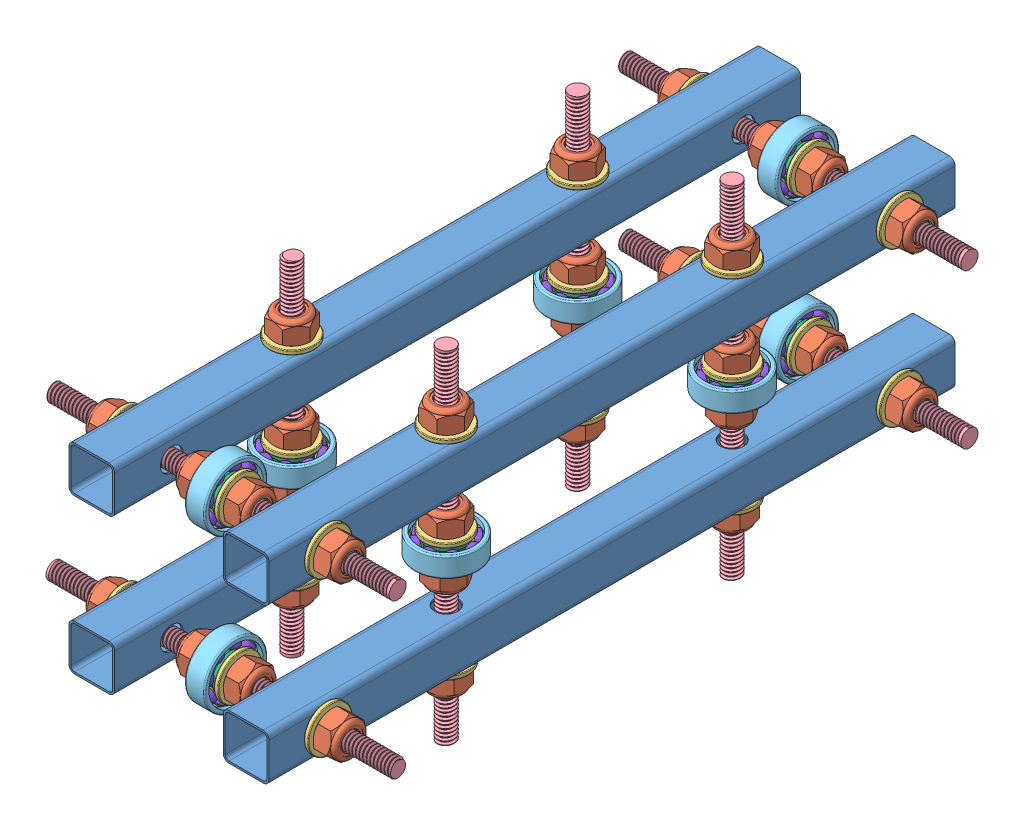
SolidWorks assembly CNC_SubAssembly_RotorArm, configuration Default. Lengths in mm.
Overall size (122.22 122.22 240).
180 component instances, 8 part files, 138 mates.
Components (placement in the parent):
- Square_Tubing_16mm-1: Square_Tubing_16mm [Default] at (-80.5305 46.7457 -574.3307) size (16 16 240)
- Square_Tubing_16mm-2: Square_Tubing_16mm [Default] at (-80.5305 -7.2543 -574.3307) size (16 16 240)
- Square_Tubing_16mm-3: Square_Tubing_16mm [Default] at (-134.5305 -7.2543 -574.3307) size (16 16 240)
- Square_Tubing_16mm-4: Square_Tubing_16mm [Default] at (-134.5305 46.7457 -574.3307) size (16 16 240)
- M8_self_lock_Nut-1: M8_self_lock_Nut [Valor predeterminado] at (-134.5305 -22.7543 -624.3307) x (0.853939 0 -0.520374) z (0 1 0) size (15.1 12 8.06)
- M8_Washer-1: M8_Washer [Default] at (-144.0305 46.7457 -674.3307) x (0 -0.853939 -0.520374) z (1 0 0) size (15.5 15.5 1.5)
- M8_self_lock_Nut-2: M8_self_lock_Nut [Valor predeterminado] at (-80.5305 -22.7543 -524.3307) x (0.853939 0 -0.520374) z (0 1 0) size (15.1 12 8.06)
- M8_self_lock_Nut-3: M8_self_lock_Nut [Valor predeterminado] at (-134.5305 62.2457 -624.3307) x (-0.430276 0 -0.902697) z (0 -1 0) size (15.1 12 8.06)
- M8_self_lock_Nut-4: M8_self_lock_Nut [Valor predeterminado] at (-80.5305 62.2457 -624.3307) x (-0.430276 0 -0.902697) z (0 -1 0) size (15.1 12 8.06)
- M8_self_lock_Nut-5: M8_self_lock_Nut [Valor predeterminado] at (-80.5305 -22.7543 -624.3307) x (0.853939 0 -0.520374) z (0 1 0) size (15.1 12 8.06)
- M8_self_lock_Nut-6: M8_self_lock_Nut [Valor predeterminado] at (-80.5305 62.2457 -524.3307) x (-0.430276 0 -0.902697) z (0 -1 0) size (15.1 12 8.06)
- M8_self_lock_Nut-7: M8_self_lock_Nut [Valor predeterminado] at (-134.5305 -22.7543 -524.3307) x (0.853939 0 -0.520374) z (0 1 0) size (15.1 12 8.06)
- M8_self_lock_Nut-8: M8_self_lock_Nut [Valor predeterminado] at (-134.5305 62.2457 -524.3307) x (-0.430276 0 -0.902697) z (0 -1 0) size (15.1 12 8.06)
- M8_Washer-2: M8_Washer [Default] at (-134.5305 56.2457 -624.3307) x (-0.853939 0 -0.520374) z (0 -1 0) size (15.5 15.5 1.5)
- M8_Washer-3: M8_Washer [Default] at (-80.5305 56.2457 -624.3307) x (-0.853939 0 -0.520374) z (0 -1 0) size (15.5 15.5 1.5)
- M8_Washer-4: M8_Washer [Default] at (-144.0305 -7.2543 -674.3307) x (0 -0.853939 -0.520374) z (1 0 0) size (15.5 15.5 1.5)
- M8_Washer-5: M8_Washer [Default] at (-72.5305 46.7457 -474.3307) x (0 -0.853939 -0.520374) z (1 0 0) size (15.5 15.5 1.5)
- M8_Washer-6: M8_Washer [Default] at (-80.5305 56.2457 -524.3307) x (-0.853939 0 -0.520374) z (0 -1 0) size (15.5 15.5 1.5)
- M8_Washer-7: M8_Washer [Default] at (-72.5305 46.7457 -674.3307) x (0 -0.853939 -0.520374) z (1 0 0) size (15.5 15.5 1.5)
- M8_Washer-8: M8_Washer [Default] at (-72.5305 -7.2543 -474.3307) x (0 -0.853939 -0.520374) z (1 0 0) size (15.5 15.5 1.5)
- M8_Washer-9: M8_Washer [Default] at (-134.5305 56.2457 -524.3307) x (-0.853939 0 -0.520374) z (0 -1 0) size (15.5 15.5 1.5)
- M8_Washer-10: M8_Washer [Default] at (-144.0305 -7.2543 -474.3307) x (0 -0.853939 -0.520374) z (1 0 0) size (15.5 15.5 1.5)
- M8_Washer-11: M8_Washer [Default] at (-144.0305 46.7457 -474.3307) x (0 -0.853939 -0.520374) z (1 0 0) size (15.5 15.5 1.5)
- M8_Washer-12: M8_Washer [Default] at (-72.5305 -7.2543 -674.3307) x (0 -0.853939 -0.520374) z (1 0 0) size (15.5 15.5 1.5)
- M8_Washer-13: M8_Washer [Default] at (-80.5305 -15.2543 -524.3307) x (-0.853939 0 -0.520374) z (0 -1 0) size (15.5 15.5 1.5)
- M8_Washer-14: M8_Washer [Default] at (-134.5305 -15.2543 -624.3307) x (-0.853939 0 -0.520374) z (0 -1 0) size (15.5 15.5 1.5)
- M8_Washer-15: M8_Washer [Default] at (-134.5305 -15.2543 -524.3307) x (-0.853939 0 -0.520374) z (0 -1 0) size (15.5 15.5 1.5)
- M8_Washer-16: M8_Washer [Default] at (-80.5305 -15.2543 -624.3307) x (-0.853939 0 -0.520374) z (0 -1 0) size (15.5 15.5 1.5)
- M8_self_lock_Nut-13: M8_self_lock_Nut [Valor predeterminado] at (-65.0305 -7.2543 -674.3307) x (0 0.669995 0.742366) z (-1 0 0) size (15.1 12 8.06)
- M8_self_lock_Nut-14: M8_self_lock_Nut [Valor predeterminado] at (-65.0305 46.7457 -474.3307) x (0 0.669995 0.742366) z (-1 0 0) size (15.1 12 8.06)
- M8_self_lock_Nut-15: M8_self_lock_Nut [Valor predeterminado] at (-65.0305 -7.2543 -474.3307) x (0 0.669995 0.742366) z (-1 0 0) size (15.1 12 8.06)
- M8_self_lock_Nut-16: M8_self_lock_Nut [Valor predeterminado] at (-65.0305 46.7457 -674.3307) x (0 0.669995 0.742366) z (-1 0 0) size (15.1 12 8.06)
- M8_self_lock_Nut-17: M8_self_lock_Nut [Valor predeterminado] at (-150.0305 46.7457 -674.3307) x (0 -0.430276 -0.902697) z (1 0 0) size (15.1 12 8.06)
- M8_self_lock_Nut-18: M8_self_lock_Nut [Valor predeterminado] at (-150.0305 -7.2543 -474.3307) x (0 -0.430276 -0.902697) z (1 0 0) size (15.1 12 8.06)
- M8_self_lock_Nut-19: M8_self_lock_Nut [Valor predeterminado] at (-150.0305 46.7457 -474.3307) x (0 -0.430276 -0.902697) z (1 0 0) size (15.1 12 8.06)
- M8_self_lock_Nut-20: M8_self_lock_Nut [Valor predeterminado] at (-150.0305 -7.2543 -674.3307) x (0 -0.430276 -0.902697) z (1 0 0) size (15.1 12 8.06)
- M8_Threaded_Rod-1: M8_Threaded_Rod [Default] at (-134.5305 -40.2543 -624.3307) size (6.18 121.11 6.93)
- M8_Threaded_Rod-2: M8_Threaded_Rod [Default] at (-167.5305 46.7457 -474.3307) x (0 -1 0) z (0 0 1) size (6.18 121.11 6.93)
- M8_Threaded_Rod-3: M8_Threaded_Rod [Default] at (-80.5305 -40.2543 -624.3307) size (6.18 121.11 6.93)
- M8_Threaded_Rod-4: M8_Threaded_Rod [Default] at (-167.5305 46.7457 -674.3307) x (0 -1 0) z (0 0 1) size (6.18 121.11 6.93)
- M8_Threaded_Rod-5: M8_Threaded_Rod [Default] at (-167.5305 -7.2543 -674.3307) x (0 -1 0) z (0 0 1) size (6.18 121.11 6.93)
- M8_Threaded_Rod-6: M8_Threaded_Rod [Default] at (-134.5305 79.7457 -524.3307) x (-1 0 0) z (0 0 1) size (6.18 121.11 6.93)
- BB_Assembly-2: BB_Assembly [Default] at (-107.5305 46.7457 -674.3307) size (7 22 22)
  - BB_OuterRing-1: BB_OuterRing [Default] at origin size (7 22 22)
  - BB_InnerRing-1: BB_InnerRing [Default] x (1 0 0) z (0 0.97954 -0.20125) size (7 13 13)
  - BB_Ball-1: BB_Ball [Default] at (0 1.61 7.8363) x (-1 0 0) z (0 -0.97954 0.20125) size (4.5 4.5 4.5)
  - BB_Cage-1: BB_Cage [Default] x (0 -0.20125 -0.97954) z (1 0 0) size (18 18 2.77)
  - BB_Ball-2: BB_Ball [Default] at (0 6.6796 4.4027) x (-1 0 0) z (0 -0.550334 0.834945) size (4.5 4.5 4.5)
  - BB_Ball-3: BB_Ball [Default] at (0 7.8363 -1.61) x (-1 0 0) z (0 0.20125 0.97954) size (4.5 4.5 4.5)
  - BB_Ball-4: BB_Ball [Default] at (0 4.4027 -6.6796) x (-1 0 0) z (0 0.834945 0.550334) size (4.5 4.5 4.5)
  - BB_Ball-5: BB_Ball [Default] at (0 -1.61 -7.8363) x (-1 0 0) z (0 0.97954 -0.20125) size (4.5 4.5 4.5)
  - BB_Ball-6: BB_Ball [Default] at (0 -6.6796 -4.4027) x (-1 0 0) z (0 0.550334 -0.834945) size (4.5 4.5 4.5)
  - BB_Ball-7: BB_Ball [Default] at (0 -7.8363 1.61) x (-1 0 0) z (0 -0.20125 -0.97954) size (4.5 4.5 4.5)
  - BB_Ball-8: BB_Ball [Default] at (0 -4.4027 6.6796) x (-1 0 0) z (0 -0.834945 -0.550334) size (4.5 4.5 4.5)
  - BB_Cage-2: BB_Cage [Default] x (0 0.20125 0.97954) z (-1 0 0) size (18 18 2.77)
- M8_Washer-18: M8_Washer [Default] at (-104.0305 46.7457 -674.3307) x (0 -0.853939 -0.520374) z (1 0 0) size (15.5 15.5 1.5)
- M8_Washer-19: M8_Washer [Default] at (-112.5305 46.7457 -674.3307) x (0 -0.853939 -0.520374) z (1 0 0) size (15.5 15.5 1.5)
- M8_self_lock_Nut-21: M8_self_lock_Nut [Valor predeterminado] at (-118.5305 46.7457 -674.3307) x (0 -0.430276 -0.902697) z (1 0 0) size (15.1 12 8.06)
- M8_self_lock_Nut-22: M8_self_lock_Nut [Valor predeterminado] at (-96.5305 46.7457 -674.3307) x (0 -0.463134 0.886288) z (-1 0 0) size (15.1 12 8.06)
- M8_self_lock_Nut-23: M8_self_lock_Nut [Valor predeterminado] at (-118.5305 46.7457 -474.3307) x (0 -0.430276 -0.902697) z (1 0 0) size (15.1 12 8.06)
- M8_Washer-20: M8_Washer [Default] at (-104.0305 46.7457 -474.3307) x (0 -0.853939 -0.520374) z (1 0 0) size (15.5 15.5 1.5)
- M8_Washer-21: M8_Washer [Default] at (-112.5305 46.7457 -474.3307) x (0 -0.853939 -0.520374) z (1 0 0) size (15.5 15.5 1.5)
- BB_Assembly-3: BB_Assembly [Default] at (-107.5305 46.7457 -474.3307) size (7 22 22)
  - BB_OuterRing-1: BB_OuterRing [Default] at origin size (7 22 22)
  - BB_InnerRing-1: BB_InnerRing [Default] x (1 0 0) z (0 0.97954 -0.20125) size (7 13 13)
  - BB_Ball-1: BB_Ball [Default] at (0 1.61 7.8363) x (-1 0 0) z (0 -0.97954 0.20125) size (4.5 4.5 4.5)
  - BB_Cage-1: BB_Cage [Default] x (0 -0.20125 -0.97954) z (1 0 0) size (18 18 2.77)
  - BB_Ball-2: BB_Ball [Default] at (0 6.6796 4.4027) x (-1 0 0) z (0 -0.550334 0.834945) size (4.5 4.5 4.5)
  - BB_Ball-3: BB_Ball [Default] at (0 7.8363 -1.61) x (-1 0 0) z (0 0.20125 0.97954) size (4.5 4.5 4.5)
  - BB_Ball-4: BB_Ball [Default] at (0 4.4027 -6.6796) x (-1 0 0) z (0 0.834945 0.550334) size (4.5 4.5 4.5)
  - BB_Ball-5: BB_Ball [Default] at (0 -1.61 -7.8363) x (-1 0 0) z (0 0.97954 -0.20125) size (4.5 4.5 4.5)
  - BB_Ball-6: BB_Ball [Default] at (0 -6.6796 -4.4027) x (-1 0 0) z (0 0.550334 -0.834945) size (4.5 4.5 4.5)
  - BB_Ball-7: BB_Ball [Default] at (0 -7.8363 1.61) x (-1 0 0) z (0 -0.20125 -0.97954) size (4.5 4.5 4.5)
  - BB_Ball-8: BB_Ball [Default] at (0 -4.4027 6.6796) x (-1 0 0) z (0 -0.834945 -0.550334) size (4.5 4.5 4.5)
  - BB_Cage-2: BB_Cage [Default] x (0 0.20125 0.97954) z (-1 0 0) size (18 18 2.77)
- M8_self_lock_Nut-24: M8_self_lock_Nut [Valor predeterminado] at (-96.5305 46.7457 -474.3307) x (0 -0.463134 0.886288) z (-1 0 0) size (15.1 12 8.06)
- M8_self_lock_Nut-25: M8_self_lock_Nut [Valor predeterminado] at (-134.5305 30.7457 -624.3307) x (-0.430276 0 -0.902697) z (0 -1 0) size (15.1 12 8.06)
- M8_Washer-22: M8_Washer [Default] at (-134.5305 16.2457 -624.3307) x (-0.853939 0 -0.520374) z (0 -1 0) size (15.5 15.5 1.5)
- M8_Washer-23: M8_Washer [Default] at (-134.5305 24.7457 -624.3307) x (-0.853939 0 -0.520374) z (0 -1 0) size (15.5 15.5 1.5)
- BB_Assembly-4: BB_Assembly [Default] at (-134.5305 19.7457 -624.3307) x (0 -1 0) z (0 0 1) size (7 22 22)
  - BB_OuterRing-1: BB_OuterRing [Default] at origin size (7 22 22)
  - BB_InnerRing-1: BB_InnerRing [Default] x (1 0 0) z (0 0.97954 -0.20125) size (7 13 13)
  - BB_Ball-1: BB_Ball [Default] at (0 1.61 7.8363) x (-1 0 0) z (0 -0.97954 0.20125) size (4.5 4.5 4.5)
  - BB_Cage-1: BB_Cage [Default] x (0 -0.20125 -0.97954) z (1 0 0) size (18 18 2.77)
  - BB_Ball-2: BB_Ball [Default] at (0 6.6796 4.4027) x (-1 0 0) z (0 -0.550334 0.834945) size (4.5 4.5 4.5)
  - BB_Ball-3: BB_Ball [Default] at (0 7.8363 -1.61) x (-1 0 0) z (0 0.20125 0.97954) size (4.5 4.5 4.5)
  - BB_Ball-4: BB_Ball [Default] at (0 4.4027 -6.6796) x (-1 0 0) z (0 0.834945 0.550334) size (4.5 4.5 4.5)
  - BB_Ball-5: BB_Ball [Default] at (0 -1.61 -7.8363) x (-1 0 0) z (0 0.97954 -0.20125) size (4.5 4.5 4.5)
  - BB_Ball-6: BB_Ball [Default] at (0 -6.6796 -4.4027) x (-1 0 0) z (0 0.550334 -0.834945) size (4.5 4.5 4.5)
  - BB_Ball-7: BB_Ball [Default] at (0 -7.8363 1.61) x (-1 0 0) z (0 -0.20125 -0.97954) size (4.5 4.5 4.5)
  - BB_Ball-8: BB_Ball [Default] at (0 -4.4027 6.6796) x (-1 0 0) z (0 -0.834945 -0.550334) size (4.5 4.5 4.5)
  - BB_Cage-2: BB_Cage [Default] x (0 0.20125 0.97954) z (-1 0 0) size (18 18 2.77)
- M8_self_lock_Nut-26: M8_self_lock_Nut [Valor predeterminado] at (-134.5305 8.7457 -624.3307) x (-0.463134 0 0.886288) z (0 1 0) size (15.1 12 8.06)
- M8_self_lock_Nut-29: M8_self_lock_Nut [Valor predeterminado] at (-96.5305 -7.2543 -674.3307) x (0 -0.463134 0.886288) z (-1 0 0) size (15.1 12 8.06)
- BB_Assembly-6: BB_Assembly [Default] at (-107.5305 -7.2543 -674.3307) size (7 22 22)
  - BB_OuterRing-1: BB_OuterRing [Default] at origin size (7 22 22)
  - BB_InnerRing-1: BB_InnerRing [Default] x (1 0 0) z (0 0.97954 -0.20125) size (7 13 13)
  - BB_Ball-1: BB_Ball [Default] at (0 1.61 7.8363) x (-1 0 0) z (0 -0.97954 0.20125) size (4.5 4.5 4.5)
  - BB_Cage-1: BB_Cage [Default] x (0 -0.20125 -0.97954) z (1 0 0) size (18 18 2.77)
  - BB_Ball-2: BB_Ball [Default] at (0 6.6796 4.4027) x (-1 0 0) z (0 -0.550334 0.834945) size (4.5 4.5 4.5)
  - BB_Ball-3: BB_Ball [Default] at (0 7.8363 -1.61) x (-1 0 0) z (0 0.20125 0.97954) size (4.5 4.5 4.5)
  - BB_Ball-4: BB_Ball [Default] at (0 4.4027 -6.6796) x (-1 0 0) z (0 0.834945 0.550334) size (4.5 4.5 4.5)
  - BB_Ball-5: BB_Ball [Default] at (0 -1.61 -7.8363) x (-1 0 0) z (0 0.97954 -0.20125) size (4.5 4.5 4.5)
  - BB_Ball-6: BB_Ball [Default] at (0 -6.6796 -4.4027) x (-1 0 0) z (0 0.550334 -0.834945) size (4.5 4.5 4.5)
  - BB_Ball-7: BB_Ball [Default] at (0 -7.8363 1.61) x (-1 0 0) z (0 -0.20125 -0.97954) size (4.5 4.5 4.5)
  - BB_Ball-8: BB_Ball [Default] at (0 -4.4027 6.6796) x (-1 0 0) z (0 -0.834945 -0.550334) size (4.5 4.5 4.5)
  - BB_Cage-2: BB_Cage [Default] x (0 0.20125 0.97954) z (-1 0 0) size (18 18 2.77)
- M8_Washer-26: M8_Washer [Default] at (-104.0305 -7.2543 -674.3307) x (0 -0.853939 -0.520374) z (1 0 0) size (15.5 15.5 1.5)
- M8_self_lock_Nut-30: M8_self_lock_Nut [Valor predeterminado] at (-118.5305 -7.2543 -674.3307) x (0 -0.430276 -0.902697) z (1 0 0) size (15.1 12 8.06)
- M8_Washer-27: M8_Washer [Default] at (-112.5305 -7.2543 -674.3307) x (0 -0.853939 -0.520374) z (1 0 0) size (15.5 15.5 1.5)
- M8_self_lock_Nut-31: M8_self_lock_Nut [Valor predeterminado] at (-80.5305 8.7457 -524.3307) x (-0.463134 0 0.886288) z (0 1 0) size (15.1 12 8.06)
- BB_Assembly-7: BB_Assembly [Default] at (-80.5305 19.7457 -524.3307) x (0 -1 0) z (0 0 1) size (7 22 22)
  - BB_OuterRing-1: BB_OuterRing [Default] at origin size (7 22 22)
  - BB_InnerRing-1: BB_InnerRing [Default] x (1 0 0) z (0 0.97954 -0.20125) size (7 13 13)
  - BB_Ball-1: BB_Ball [Default] at (0 1.61 7.8363) x (-1 0 0) z (0 -0.97954 0.20125) size (4.5 4.5 4.5)
  - BB_Cage-1: BB_Cage [Default] x (0 -0.20125 -0.97954) z (1 0 0) size (18 18 2.77)
  - BB_Ball-2: BB_Ball [Default] at (0 6.6796 4.4027) x (-1 0 0) z (0 -0.550334 0.834945) size (4.5 4.5 4.5)
  - BB_Ball-3: BB_Ball [Default] at (0 7.8363 -1.61) x (-1 0 0) z (0 0.20125 0.97954) size (4.5 4.5 4.5)
  - BB_Ball-4: BB_Ball [Default] at (0 4.4027 -6.6796) x (-1 0 0) z (0 0.834945 0.550334) size (4.5 4.5 4.5)
  - BB_Ball-5: BB_Ball [Default] at (0 -1.61 -7.8363) x (-1 0 0) z (0 0.97954 -0.20125) size (4.5 4.5 4.5)
  - BB_Ball-6: BB_Ball [Default] at (0 -6.6796 -4.4027) x (-1 0 0) z (0 0.550334 -0.834945) size (4.5 4.5 4.5)
  - BB_Ball-7: BB_Ball [Default] at (0 -7.8363 1.61) x (-1 0 0) z (0 -0.20125 -0.97954) size (4.5 4.5 4.5)
  - BB_Ball-8: BB_Ball [Default] at (0 -4.4027 6.6796) x (-1 0 0) z (0 -0.834945 -0.550334) size (4.5 4.5 4.5)
  - BB_Cage-2: BB_Cage [Default] x (0 0.20125 0.97954) z (-1 0 0) size (18 18 2.77)
- M8_Washer-28: M8_Washer [Default] at (-80.5305 16.2457 -524.3307) x (-0.853939 0 -0.520374) z (0 -1 0) size (15.5 15.5 1.5)
- M8_self_lock_Nut-32: M8_self_lock_Nut [Valor predeterminado] at (-80.5305 30.7457 -524.3307) x (-0.430276 0 -0.902697) z (0 -1 0) size (15.1 12 8.06)
- M8_Washer-29: M8_Washer [Default] at (-80.5305 24.7457 -524.3307) x (-0.853939 0 -0.520374) z (0 -1 0) size (15.5 15.5 1.5)
- M8_self_lock_Nut-33: M8_self_lock_Nut [Valor predeterminado] at (-118.5305 -7.2543 -474.3307) x (0 -0.430276 -0.902697) z (1 0 0) size (15.1 12 8.06)
- M8_Washer-30: M8_Washer [Default] at (-104.0305 -7.2543 -474.3307) x (0 -0.853939 -0.520374) z (1 0 0) size (15.5 15.5 1.5)
- M8_Washer-31: M8_Washer [Default] at (-112.5305 -7.2543 -474.3307) x (0 -0.853939 -0.520374) z (1 0 0) size (15.5 15.5 1.5)
- BB_Assembly-8: BB_Assembly [Default] at (-107.5305 -7.2543 -474.3307) size (7 22 22)
  - BB_OuterRing-1: BB_OuterRing [Default] at origin size (7 22 22)
  - BB_InnerRing-1: BB_InnerRing [Default] x (1 0 0) z (0 0.97954 -0.20125) size (7 13 13)
  - BB_Ball-1: BB_Ball [Default] at (0 1.61 7.8363) x (-1 0 0) z (0 -0.97954 0.20125) size (4.5 4.5 4.5)
  - BB_Cage-1: BB_Cage [Default] x (0 -0.20125 -0.97954) z (1 0 0) size (18 18 2.77)
  - BB_Ball-2: BB_Ball [Default] at (0 6.6796 4.4027) x (-1 0 0) z (0 -0.550334 0.834945) size (4.5 4.5 4.5)
  - BB_Ball-3: BB_Ball [Default] at (0 7.8363 -1.61) x (-1 0 0) z (0 0.20125 0.97954) size (4.5 4.5 4.5)
  - BB_Ball-4: BB_Ball [Default] at (0 4.4027 -6.6796) x (-1 0 0) z (0 0.834945 0.550334) size (4.5 4.5 4.5)
  - BB_Ball-5: BB_Ball [Default] at (0 -1.61 -7.8363) x (-1 0 0) z (0 0.97954 -0.20125) size (4.5 4.5 4.5)
  - BB_Ball-6: BB_Ball [Default] at (0 -6.6796 -4.4027) x (-1 0 0) z (0 0.550334 -0.834945) size (4.5 4.5 4.5)
  - BB_Ball-7: BB_Ball [Default] at (0 -7.8363 1.61) x (-1 0 0) z (0 -0.20125 -0.97954) size (4.5 4.5 4.5)
  - BB_Ball-8: BB_Ball [Default] at (0 -4.4027 6.6796) x (-1 0 0) z (0 -0.834945 -0.550334) size (4.5 4.5 4.5)
  - BB_Cage-2: BB_Cage [Default] x (0 0.20125 0.97954) z (-1 0 0) size (18 18 2.77)
- M8_self_lock_Nut-34: M8_self_lock_Nut [Valor predeterminado] at (-96.5305 -7.2543 -474.3307) x (0 -0.463134 0.886288) z (-1 0 0) size (15.1 12 8.06)
- M8_self_lock_Nut-35: M8_self_lock_Nut [Valor predeterminado] at (-134.5305 8.7457 -524.3307) x (0.430276 0 -0.902697) z (0 1 0) size (15.1 12 8.06)
- M8_Washer-32: M8_Washer [Default] at (-134.5305 23.2457 -524.3307) x (0.853939 0 -0.520374) z (0 1 0) size (15.5 15.5 1.5)
- M8_Washer-33: M8_Washer [Default] at (-134.5305 14.7457 -524.3307) x (0.853939 0 -0.520374) z (0 1 0) size (15.5 15.5 1.5)
- BB_Assembly-9: BB_Assembly [Default] at (-134.5305 19.7457 -524.3307) x (0 1 0) z (0 0 1) size (7 22 22)
  - BB_OuterRing-1: BB_OuterRing [Default] at origin size (7 22 22)
  - BB_InnerRing-1: BB_InnerRing [Default] x (1 0 0) z (0 0.97954 -0.20125) size (7 13 13)
  - BB_Ball-1: BB_Ball [Default] at (0 1.61 7.8363) x (-1 0 0) z (0 -0.97954 0.20125) size (4.5 4.5 4.5)
  - BB_Cage-1: BB_Cage [Default] x (0 -0.20125 -0.97954) z (1 0 0) size (18 18 2.77)
  - BB_Ball-2: BB_Ball [Default] at (0 6.6796 4.4027) x (-1 0 0) z (0 -0.550334 0.834945) size (4.5 4.5 4.5)
  - BB_Ball-3: BB_Ball [Default] at (0 7.8363 -1.61) x (-1 0 0) z (0 0.20125 0.97954) size (4.5 4.5 4.5)
  - BB_Ball-4: BB_Ball [Default] at (0 4.4027 -6.6796) x (-1 0 0) z (0 0.834945 0.550334) size (4.5 4.5 4.5)
  - BB_Ball-5: BB_Ball [Default] at (0 -1.61 -7.8363) x (-1 0 0) z (0 0.97954 -0.20125) size (4.5 4.5 4.5)
  - BB_Ball-6: BB_Ball [Default] at (0 -6.6796 -4.4027) x (-1 0 0) z (0 0.550334 -0.834945) size (4.5 4.5 4.5)
  - BB_Ball-7: BB_Ball [Default] at (0 -7.8363 1.61) x (-1 0 0) z (0 -0.20125 -0.97954) size (4.5 4.5 4.5)
  - BB_Ball-8: BB_Ball [Default] at (0 -4.4027 6.6796) x (-1 0 0) z (0 -0.834945 -0.550334) size (4.5 4.5 4.5)
  - BB_Cage-2: BB_Cage [Default] x (0 0.20125 0.97954) z (-1 0 0) size (18 18 2.77)
- M8_self_lock_Nut-36: M8_self_lock_Nut [Valor predeterminado] at (-134.5305 30.7457 -524.3307) x (0.463134 0 0.886288) z (0 -1 0) size (15.1 12 8.06)
- M8_self_lock_Nut-37: M8_self_lock_Nut [Valor predeterminado] at (-80.5305 30.7457 -624.3307) x (-0.430276 0 -0.902697) z (0 -1 0) size (15.1 12 8.06)
- M8_Washer-34: M8_Washer [Default] at (-80.5305 16.2457 -624.3307) x (-0.853939 0 -0.520374) z (0 -1 0) size (15.5 15.5 1.5)
- M8_Washer-35: M8_Washer [Default] at (-80.5305 24.7457 -624.3307) x (-0.853939 0 -0.520374) z (0 -1 0) size (15.5 15.5 1.5)
- BB_Assembly-10: BB_Assembly [Default] at (-80.5305 19.7457 -624.3307) x (0 -1 0) z (0 0 1) size (7 22 22)
  - BB_OuterRing-1: BB_OuterRing [Default] at origin size (7 22 22)
  - BB_InnerRing-1: BB_InnerRing [Default] x (1 0 0) z (0 0.97954 -0.20125) size (7 13 13)
  - BB_Ball-1: BB_Ball [Default] at (0 1.61 7.8363) x (-1 0 0) z (0 -0.97954 0.20125) size (4.5 4.5 4.5)
  - BB_Cage-1: BB_Cage [Default] x (0 -0.20125 -0.97954) z (1 0 0) size (18 18 2.77)
  - BB_Ball-2: BB_Ball [Default] at (0 6.6796 4.4027) x (-1 0 0) z (0 -0.550334 0.834945) size (4.5 4.5 4.5)
  - BB_Ball-3: BB_Ball [Default] at (0 7.8363 -1.61) x (-1 0 0) z (0 0.20125 0.97954) size (4.5 4.5 4.5)
  - BB_Ball-4: BB_Ball [Default] at (0 4.4027 -6.6796) x (-1 0 0) z (0 0.834945 0.550334) size (4.5 4.5 4.5)
  - BB_Ball-5: BB_Ball [Default] at (0 -1.61 -7.8363) x (-1 0 0) z (0 0.97954 -0.20125) size (4.5 4.5 4.5)
  - BB_Ball-6: BB_Ball [Default] at (0 -6.6796 -4.4027) x (-1 0 0) z (0 0.550334 -0.834945) size (4.5 4.5 4.5)
  - BB_Ball-7: BB_Ball [Default] at (0 -7.8363 1.61) x (-1 0 0) z (0 -0.20125 -0.97954) size (4.5 4.5 4.5)
  - BB_Ball-8: BB_Ball [Default] at (0 -4.4027 6.6796) x (-1 0 0) z (0 -0.834945 -0.550334) size (4.5 4.5 4.5)
  - BB_Cage-2: BB_Cage [Default] x (0 0.20125 0.97954) z (-1 0 0) size (18 18 2.77)
- M8_self_lock_Nut-38: M8_self_lock_Nut [Valor predeterminado] at (-80.5305 8.7457 -624.3307) x (-0.463134 0 0.886288) z (0 1 0) size (15.1 12 8.06)
- M8_Threaded_Rod-7: M8_Threaded_Rod [Default] at (-80.5305 -40.2543 -524.3307) size (6.18 121.11 6.93)
- M8_Threaded_Rod-8: M8_Threaded_Rod [Default] at (-47.5305 -7.2543 -474.3307) x (0 1 0) z (0 0 1) size (6.18 121.11 6.93)
Mates (geometry in assembly coordinates):
- Coincident1: coincident anti-aligned: plane of Square_Tubing_16mm-4 through (-140.5305 54.7457 -694.3307) normal (0 1 0); plane of M8_Washer-2 through (-134.5305 54.7457 -624.3307) normal (0 -1 0)
- Coincident2: coincident anti-aligned: plane of Square_Tubing_16mm-4 through (-140.5305 54.7457 -694.3307) normal (0 1 0); plane of M8_Washer-9 through (-134.5305 54.7457 -524.3307) normal (0 -1 0)
- Coincident3: coincident anti-aligned: plane of Square_Tubing_16mm-1 through (-86.5305 54.7457 -694.3307) normal (0 1 0); plane of M8_Washer-6 through (-80.5305 54.7457 -524.3307) normal (0 -1 0)
- Coincident4: coincident anti-aligned: plane of Square_Tubing_16mm-1 through (-72.5305 40.7457 -694.3307) normal (1 0 0); plane of M8_Washer-7 through (-72.5305 46.7457 -674.3307) normal (-1 0 0)
- Coincident5: coincident anti-aligned: plane of Square_Tubing_16mm-1 through (-86.5305 54.7457 -694.3307) normal (0 1 0); plane of M8_Washer-3 through (-80.5305 54.7457 -624.3307) normal (0 -1 0)
- Coincident6: coincident anti-aligned: plane of Square_Tubing_16mm-2 through (-72.5305 -13.2543 -694.3307) normal (1 0 0); plane of M8_Washer-8 through (-72.5305 -7.2543 -474.3307) normal (-1 0 0)
- Coincident7: coincident anti-aligned: plane of Square_Tubing_16mm-2 through (-72.5305 -13.2543 -694.3307) normal (1 0 0); plane of M8_Washer-12 through (-72.5305 -7.2543 -674.3307) normal (-1 0 0)
- Coincident8: coincident anti-aligned: plane of Square_Tubing_16mm-4 through (-142.5305 40.7457 -694.3307) normal (-1 0 0); plane of M8_Washer-1 through (-142.5305 46.7457 -674.3307) normal (1 0 0)
- Coincident9: coincident anti-aligned: plane of Square_Tubing_16mm-3 through (-142.5305 -13.2543 -694.3307) normal (-1 0 0); plane of M8_Washer-4 through (-142.5305 -7.2543 -674.3307) normal (1 0 0)
- Coincident10: coincident anti-aligned: plane of Square_Tubing_16mm-3 through (-140.5305 -15.2543 -694.3307) normal (0 -1 0); plane of M8_Washer-14 through (-134.5305 -15.2543 -624.3307) normal (0 1 0)
- Coincident11: coincident anti-aligned: plane of Square_Tubing_16mm-2 through (-86.5305 -15.2543 -694.3307) normal (0 -1 0); plane of M8_Washer-16 through (-80.5305 -15.2543 -624.3307) normal (0 1 0)
- Coincident12: coincident anti-aligned: plane of Square_Tubing_16mm-2 through (-86.5305 -15.2543 -694.3307) normal (0 -1 0); plane of M8_Washer-13 through (-80.5305 -15.2543 -524.3307) normal (0 1 0)
- Coincident13: coincident anti-aligned: plane of Square_Tubing_16mm-3 through (-140.5305 -15.2543 -694.3307) normal (0 -1 0); plane of M8_Washer-15 through (-134.5305 -15.2543 -524.3307) normal (0 1 0)
- Coincident14: coincident anti-aligned: plane of Square_Tubing_16mm-4 through (-142.5305 40.7457 -694.3307) normal (-1 0 0); plane of M8_Washer-11 through (-142.5305 46.7457 -474.3307) normal (1 0 0)
- Coincident15: coincident anti-aligned: plane of Square_Tubing_16mm-3 through (-142.5305 -13.2543 -694.3307) normal (-1 0 0); plane of M8_Washer-10 through (-142.5305 -7.2543 -474.3307) normal (1 0 0)
- Coincident16: coincident anti-aligned: plane of Square_Tubing_16mm-1 through (-72.5305 40.7457 -694.3307) normal (1 0 0); plane of M8_Washer-5 through (-72.5305 46.7457 -474.3307) normal (-1 0 0)
- Coincident17: coincident anti-aligned: plane of M8_self_lock_Nut-2 through (-80.5305 -16.7543 -524.3307) normal (0 1 0); plane of M8_Washer-13 through (-80.5305 -16.7543 -524.3307) normal (0 -1 0)
- Coincident18: coincident anti-aligned: plane of M8_self_lock_Nut-7 through (-134.5305 -16.7543 -524.3307) normal (0 1 0); plane of M8_Washer-15 through (-134.5305 -16.7543 -524.3307) normal (0 -1 0)
- Coincident19: coincident anti-aligned: plane of M8_self_lock_Nut-1 through (-134.5305 -16.7543 -624.3307) normal (0 1 0); plane of M8_Washer-14 through (-134.5305 -16.7543 -624.3307) normal (0 -1 0)
- Coincident20: coincident anti-aligned: plane of M8_self_lock_Nut-5 through (-80.5305 -16.7543 -624.3307) normal (0 1 0); plane of M8_Washer-16 through (-80.5305 -16.7543 -624.3307) normal (0 -1 0)
- Coincident25: coincident anti-aligned: plane of M8_self_lock_Nut-8 through (-134.5305 56.2457 -524.3307) normal (0 -1 0); plane of M8_Washer-9 through (-134.5305 56.2457 -524.3307) normal (0 1 0)
- Coincident26: coincident anti-aligned: plane of M8_self_lock_Nut-3 through (-134.5305 56.2457 -624.3307) normal (0 -1 0); plane of M8_Washer-2 through (-134.5305 56.2457 -624.3307) normal (0 1 0)
- Coincident27: coincident anti-aligned: plane of M8_self_lock_Nut-4 through (-80.5305 56.2457 -624.3307) normal (0 -1 0); plane of M8_Washer-3 through (-80.5305 56.2457 -624.3307) normal (0 1 0)
- Coincident29: coincident anti-aligned: plane of M8_self_lock_Nut-6 through (-80.5305 56.2457 -524.3307) normal (0 -1 0); plane of M8_Washer-6 through (-80.5305 56.2457 -524.3307) normal (0 1 0)
- Coincident30: coincident anti-aligned: plane of M8_Washer-12 through (-71.0305 -7.2543 -674.3307) normal (1 0 0); plane of M8_self_lock_Nut-13 through (-71.0305 -7.2543 -674.3307) normal (-1 0 0)
- Coincident31: coincident anti-aligned: plane of M8_Washer-7 through (-71.0305 46.7457 -674.3307) normal (1 0 0); plane of M8_self_lock_Nut-16 through (-71.0305 46.7457 -674.3307) normal (-1 0 0)
- Coincident32: coincident anti-aligned: plane of M8_Washer-5 through (-71.0305 46.7457 -474.3307) normal (1 0 0); plane of M8_self_lock_Nut-14 through (-71.0305 46.7457 -474.3307) normal (-1 0 0)
- Coincident33: coincident anti-aligned: plane of M8_Washer-8 through (-71.0305 -7.2543 -474.3307) normal (1 0 0); plane of M8_self_lock_Nut-15 through (-71.0305 -7.2543 -474.3307) normal (-1 0 0)
- Coincident34: coincident anti-aligned: plane of M8_Washer-1 through (-144.0305 46.7457 -674.3307) normal (-1 0 0); plane of M8_self_lock_Nut-17 through (-144.0305 46.7457 -674.3307) normal (1 0 0)
- Coincident35: coincident anti-aligned: plane of M8_Washer-10 through (-144.0305 -7.2543 -474.3307) normal (-1 0 0); plane of M8_self_lock_Nut-18 through (-144.0305 -7.2543 -474.3307) normal (1 0 0)
- Coincident36: coincident anti-aligned: plane of M8_Washer-11 through (-144.0305 46.7457 -474.3307) normal (-1 0 0); plane of M8_self_lock_Nut-19 through (-144.0305 46.7457 -474.3307) normal (1 0 0)
- Coincident37: coincident anti-aligned: plane of M8_Washer-4 through (-144.0305 -7.2543 -674.3307) normal (-1 0 0); plane of M8_self_lock_Nut-20 through (-144.0305 -7.2543 -674.3307) normal (1 0 0)
- Lock3: lock: unknown of Square_Tubing_16mm-1; unknown of Square_Tubing_16mm-4
- Lock5: lock: unknown of Square_Tubing_16mm-2; unknown of Square_Tubing_16mm-3
- Lock6: lock: unknown of Square_Tubing_16mm-3; unknown of Square_Tubing_16mm-4
- Lock7: lock: unknown of Square_Tubing_16mm-1; unknown of Square_Tubing_16mm-2
- Coincident40: coincident anti-aligned: plane of BB_Assembly-2/BB_InnerRing-1 through (-104.0305 45.7394 -679.2284) normal (1 0 0); plane of M8_Washer-18 through (-104.0305 46.7457 -674.3307) normal (-1 0 0)
- Concentric51: concentric aligned: cylinder of BB_Assembly-2/BB_InnerRing-1 through (-149.9214 46.7457 -674.3307) axis (-1 0 0) radius 5; cylinder of M8_Washer-18 through (-102.5305 46.7457 -674.3307) axis (-1 0 0) radius 4.125
- Concentric52: concentric aligned: cylinder of BB_Assembly-2/BB_InnerRing-1 through (-149.9214 46.7457 -674.3307) axis (-1 0 0) radius 5; cylinder of M8_Washer-19 through (-111.0305 46.7457 -674.3307) axis (-1 0 0) radius 4.125
- Coincident41: coincident anti-aligned: plane of BB_Assembly-2/BB_InnerRing-1 through (-111.0305 45.7394 -679.2284) normal (-1 0 0); plane of M8_Washer-19 through (-111.0305 46.7457 -674.3307) normal (1 0 0)
- Coincident42: coincident anti-aligned: plane of M8_Washer-19 through (-112.5305 46.7457 -674.3307) normal (-1 0 0); plane of M8_self_lock_Nut-21 through (-112.5305 46.7457 -674.3307) normal (1 0 0)
- Concentric53: concentric anti-aligned: cylinder of BB_Assembly-2/BB_InnerRing-1 through (-149.9214 46.7457 -674.3307) axis (-1 0 0) radius 5; cylinder of M8_self_lock_Nut-21 through (-107.5529 46.7457 -674.3307) axis (1 0 0) radius 3.4
- Coincident43: coincident anti-aligned: plane of M8_Washer-18 through (-102.5305 46.7457 -674.3307) normal (1 0 0); plane of M8_self_lock_Nut-22 through (-102.5305 46.7457 -674.3307) normal (-1 0 0)
- Concentric54: concentric aligned: cylinder of BB_Assembly-2/BB_InnerRing-1 through (-149.9214 46.7457 -674.3307) axis (-1 0 0) radius 5; cylinder of M8_self_lock_Nut-22 through (-107.5081 46.7457 -674.3307) axis (-1 0 0) radius 3.4
- Concentric55: concentric aligned: cylinder of BB_Assembly-3/BB_InnerRing-1 through (-149.9214 46.7457 -474.3307) axis (-1 0 0) radius 5; cylinder of M8_self_lock_Nut-24 through (-107.5081 46.7457 -474.3307) axis (-1 0 0) radius 3.4
- Concentric56: concentric anti-aligned: cylinder of M8_self_lock_Nut-23 through (-107.5529 46.7457 -474.3307) axis (1 0 0) radius 3.4; cylinder of BB_Assembly-3/BB_InnerRing-1 through (-149.9214 46.7457 -474.3307) axis (-1 0 0) radius 5
- Concentric57: concentric aligned: cylinder of M8_Washer-20 through (-102.5305 46.7457 -474.3307) axis (-1 0 0) radius 4.125; cylinder of BB_Assembly-3/BB_InnerRing-1 through (-149.9214 46.7457 -474.3307) axis (-1 0 0) radius 5
- Concentric58: concentric aligned: cylinder of M8_Washer-21 through (-111.0305 46.7457 -474.3307) axis (-1 0 0) radius 4.125; cylinder of BB_Assembly-3/BB_InnerRing-1 through (-149.9214 46.7457 -474.3307) axis (-1 0 0) radius 5
- Coincident44: coincident anti-aligned: plane of M8_Washer-20 through (-104.0305 46.7457 -474.3307) normal (-1 0 0); plane of BB_Assembly-3/BB_InnerRing-1 through (-104.0305 45.7394 -479.2284) normal (1 0 0)
- Coincident45: coincident anti-aligned: plane of M8_Washer-20 through (-102.5305 46.7457 -474.3307) normal (1 0 0); plane of M8_self_lock_Nut-24 through (-102.5305 46.7457 -474.3307) normal (-1 0 0)
- Coincident46: coincident anti-aligned: plane of M8_Washer-21 through (-111.0305 46.7457 -474.3307) normal (1 0 0); plane of BB_Assembly-3/BB_InnerRing-1 through (-111.0305 45.7394 -479.2284) normal (-1 0 0)
- Coincident47: coincident anti-aligned: plane of M8_self_lock_Nut-23 through (-112.5305 46.7457 -474.3307) normal (1 0 0); plane of M8_Washer-21 through (-112.5305 46.7457 -474.3307) normal (-1 0 0)
- Concentric59: concentric aligned: cylinder of BB_Assembly-4/BB_InnerRing-1 through (-134.5305 62.1366 -624.3307) axis (0 1 0) radius 5; cylinder of M8_self_lock_Nut-26 through (-134.5305 19.7232 -624.3307) axis (0 1 0) radius 3.4
- Concentric60: concentric anti-aligned: cylinder of M8_self_lock_Nut-25 through (-134.5305 19.7681 -624.3307) axis (0 -1 0) radius 3.4; cylinder of BB_Assembly-4/BB_InnerRing-1 through (-134.5305 62.1366 -624.3307) axis (0 1 0) radius 5
- Concentric61: concentric aligned: cylinder of M8_Washer-22 through (-134.5305 14.7457 -624.3307) axis (0 1 0) radius 4.125; cylinder of BB_Assembly-4/BB_InnerRing-1 through (-134.5305 62.1366 -624.3307) axis (0 1 0) radius 5
- Concentric62: concentric aligned: cylinder of M8_Washer-23 through (-134.5305 23.2457 -624.3307) axis (0 1 0) radius 4.125; cylinder of BB_Assembly-4/BB_InnerRing-1 through (-134.5305 62.1366 -624.3307) axis (0 1 0) radius 5
- Coincident48: coincident anti-aligned: plane of M8_Washer-22 through (-134.5305 16.2457 -624.3307) normal (0 1 0); plane of BB_Assembly-4/BB_InnerRing-1 through (-135.5368 16.2457 -629.2284) normal (0 -1 0)
- Coincident49: coincident anti-aligned: plane of M8_Washer-22 through (-134.5305 14.7457 -624.3307) normal (0 -1 0); plane of M8_self_lock_Nut-26 through (-134.5305 14.7457 -624.3307) normal (0 1 0)
- Coincident50: coincident anti-aligned: plane of M8_Washer-23 through (-134.5305 23.2457 -624.3307) normal (0 -1 0); plane of BB_Assembly-4/BB_InnerRing-1 through (-135.5368 23.2457 -629.2284) normal (0 1 0)
- Coincident51: coincident anti-aligned: plane of M8_self_lock_Nut-25 through (-134.5305 24.7457 -624.3307) normal (0 -1 0); plane of M8_Washer-23 through (-134.5305 24.7457 -624.3307) normal (0 1 0)
- Concentric63: concentric aligned: cylinder of BB_Assembly-5/BB_InnerRing-1 through (-709.6968 -142.3165 -1634.6078) axis (-1 0 0) radius 5; cylinder of M8_self_lock_Nut-28 through (-667.2835 -142.3165 -1634.6078) axis (-1 0 0) radius 3.4
- Concentric65: concentric aligned: cylinder of M8_Washer-24 through (-662.3059 -142.3165 -1634.6078) axis (-1 0 0) radius 4.125; cylinder of BB_Assembly-5/BB_InnerRing-1 through (-709.6968 -142.3165 -1634.6078) axis (-1 0 0) radius 5
- Concentric66: concentric aligned: cylinder of M8_Washer-25 through (-670.8059 -142.3165 -1634.6078) axis (-1 0 0) radius 4.125; cylinder of BB_Assembly-5/BB_InnerRing-1 through (-709.6968 -142.3165 -1634.6078) axis (-1 0 0) radius 5
- Coincident52: coincident anti-aligned: plane of M8_Washer-24 through (-663.8059 -142.3165 -1634.6078) normal (-1 0 0); plane of BB_Assembly-5/BB_InnerRing-1 through (-663.8059 -143.3228 -1639.5055) normal (1 0 0)
- Coincident53: coincident anti-aligned: plane of M8_Washer-24 through (-662.3059 -142.3165 -1634.6078) normal (1 0 0); plane of M8_self_lock_Nut-28 through (-662.3059 -142.3165 -1634.6078) normal (-1 0 0)
- Coincident54: coincident anti-aligned: plane of M8_Washer-25 through (-670.8059 -142.3165 -1634.6078) normal (1 0 0); plane of BB_Assembly-5/BB_InnerRing-1 through (-670.8059 -143.3228 -1639.5055) normal (-1 0 0)
- Concentric67: concentric aligned: cylinder of BB_Assembly-6/BB_InnerRing-1 through (-149.9214 -7.2543 -674.3307) axis (-1 0 0) radius 5; cylinder of M8_Washer-27 through (-111.0305 -7.2543 -674.3307) axis (-1 0 0) radius 4.125
- Concentric68: concentric aligned: cylinder of M8_self_lock_Nut-29 through (-107.5081 -7.2543 -674.3307) axis (-1 0 0) radius 3.4; cylinder of BB_Assembly-6/BB_InnerRing-1 through (-149.9214 -7.2543 -674.3307) axis (-1 0 0) radius 5
- Concentric69: concentric anti-aligned: cylinder of BB_Assembly-6/BB_InnerRing-1 through (-149.9214 -7.2543 -674.3307) axis (-1 0 0) radius 5; cylinder of M8_self_lock_Nut-30 through (-107.5529 -7.2543 -674.3307) axis (1 0 0) radius 3.4
- Concentric70: concentric aligned: cylinder of BB_Assembly-6/BB_InnerRing-1 through (-149.9214 -7.2543 -674.3307) axis (-1 0 0) radius 5; cylinder of M8_Washer-26 through (-102.5305 -7.2543 -674.3307) axis (-1 0 0) radius 4.125
- Coincident56: coincident anti-aligned: plane of BB_Assembly-6/BB_InnerRing-1 through (-104.0305 -8.2606 -679.2284) normal (1 0 0); plane of M8_Washer-26 through (-104.0305 -7.2543 -674.3307) normal (-1 0 0)
- Coincident57: coincident anti-aligned: plane of BB_Assembly-6/BB_InnerRing-1 through (-111.0305 -8.2606 -679.2284) normal (-1 0 0); plane of M8_Washer-27 through (-111.0305 -7.2543 -674.3307) normal (1 0 0)
- Coincident58: coincident anti-aligned: plane of M8_self_lock_Nut-29 through (-102.5305 -7.2543 -674.3307) normal (-1 0 0); plane of M8_Washer-26 through (-102.5305 -7.2543 -674.3307) normal (1 0 0)
- Coincident59: coincident anti-aligned: plane of M8_self_lock_Nut-30 through (-112.5305 -7.2543 -674.3307) normal (1 0 0); plane of M8_Washer-27 through (-112.5305 -7.2543 -674.3307) normal (-1 0 0)
- Concentric71: concentric aligned: cylinder of BB_Assembly-7/BB_InnerRing-1 through (-80.5305 62.1366 -524.3307) axis (0 1 0) radius 5; cylinder of M8_Washer-29 through (-80.5305 23.2457 -524.3307) axis (0 1 0) radius 4.125
- Concentric72: concentric aligned: cylinder of M8_self_lock_Nut-31 through (-80.5305 19.7232 -524.3307) axis (0 1 0) radius 3.4; cylinder of BB_Assembly-7/BB_InnerRing-1 through (-80.5305 62.1366 -524.3307) axis (0 1 0) radius 5
- Concentric73: concentric anti-aligned: cylinder of BB_Assembly-7/BB_InnerRing-1 through (-80.5305 62.1366 -524.3307) axis (0 1 0) radius 5; cylinder of M8_self_lock_Nut-32 through (-80.5305 19.7681 -524.3307) axis (0 -1 0) radius 3.4
- Concentric74: concentric aligned: cylinder of BB_Assembly-7/BB_InnerRing-1 through (-80.5305 62.1366 -524.3307) axis (0 1 0) radius 5; cylinder of M8_Washer-28 through (-80.5305 14.7457 -524.3307) axis (0 1 0) radius 4.125
- Coincident60: coincident anti-aligned: plane of BB_Assembly-7/BB_InnerRing-1 through (-81.5368 16.2457 -529.2284) normal (0 -1 0); plane of M8_Washer-28 through (-80.5305 16.2457 -524.3307) normal (0 1 0)
- Coincident61: coincident anti-aligned: plane of BB_Assembly-7/BB_InnerRing-1 through (-81.5368 23.2457 -529.2284) normal (0 1 0); plane of M8_Washer-29 through (-80.5305 23.2457 -524.3307) normal (0 -1 0)
- Coincident62: coincident anti-aligned: plane of M8_self_lock_Nut-31 through (-80.5305 14.7457 -524.3307) normal (0 1 0); plane of M8_Washer-28 through (-80.5305 14.7457 -524.3307) normal (0 -1 0)
- Coincident63: coincident anti-aligned: plane of M8_self_lock_Nut-32 through (-80.5305 24.7457 -524.3307) normal (0 -1 0); plane of M8_Washer-29 through (-80.5305 24.7457 -524.3307) normal (0 1 0)
- Concentric75: concentric anti-aligned: cylinder of M8_self_lock_Nut-33 through (-107.5529 -2.7637 -481.7488) axis (1 0 0) radius 3.4; cylinder of BB_Assembly-8/BB_InnerRing-1 through (-149.9214 -2.7637 -481.7488) axis (-1 0 0) radius 5
- Concentric76: concentric aligned: cylinder of M8_Washer-31 through (-111.0305 -2.7637 -481.7488) axis (-1 0 0) radius 4.125; cylinder of BB_Assembly-8/BB_InnerRing-1 through (-149.9214 -2.7637 -481.7488) axis (-1 0 0) radius 5
- Concentric77: concentric aligned: cylinder of BB_Assembly-8/BB_InnerRing-1 through (-149.9214 -2.7637 -481.7488) axis (-1 0 0) radius 5; cylinder of M8_self_lock_Nut-34 through (-107.5081 -2.7637 -481.7488) axis (-1 0 0) radius 3.4
- Concentric78: concentric aligned: cylinder of M8_Washer-30 through (-102.5305 -2.7637 -481.7488) axis (-1 0 0) radius 4.125; cylinder of BB_Assembly-8/BB_InnerRing-1 through (-149.9214 -2.7637 -481.7488) axis (-1 0 0) radius 5
- Coincident64: coincident anti-aligned: plane of M8_Washer-30 through (-104.0305 -2.7637 -481.7488) normal (-1 0 0); plane of BB_Assembly-8/BB_InnerRing-1 through (-104.0305 -3.77 -486.6465) normal (1 0 0)
- Coincident65: coincident anti-aligned: plane of M8_Washer-30 through (-102.5305 -2.7637 -481.7488) normal (1 0 0); plane of M8_self_lock_Nut-34 through (-102.5305 -2.7637 -481.7488) normal (-1 0 0)
- Coincident66: coincident anti-aligned: plane of M8_self_lock_Nut-33 through (-112.5305 -2.7637 -481.7488) normal (1 0 0); plane of M8_Washer-31 through (-112.5305 -2.7637 -481.7488) normal (-1 0 0)
- Coincident67: coincident anti-aligned: plane of M8_Washer-31 through (-111.0305 -2.7637 -481.7488) normal (1 0 0); plane of BB_Assembly-8/BB_InnerRing-1 through (-111.0305 -3.77 -486.6465) normal (-1 0 0)
- Concentric79: concentric anti-aligned: cylinder of M8_self_lock_Nut-35 through (-134.5305 19.7232 -524.3307) axis (0 1 0) radius 3.4; cylinder of BB_Assembly-9/BB_InnerRing-1 through (-134.5305 -22.6453 -524.3307) axis (0 -1 0) radius 5
- Concentric80: concentric aligned: cylinder of M8_Washer-33 through (-134.5305 16.2457 -524.3307) axis (0 -1 0) radius 4.125; cylinder of BB_Assembly-9/BB_InnerRing-1 through (-134.5305 -22.6453 -524.3307) axis (0 -1 0) radius 5
- Concentric81: concentric aligned: cylinder of BB_Assembly-9/BB_InnerRing-1 through (-134.5305 -22.6453 -524.3307) axis (0 -1 0) radius 5; cylinder of M8_self_lock_Nut-36 through (-134.5305 19.7681 -524.3307) axis (0 -1 0) radius 3.4
- Concentric82: concentric aligned: cylinder of M8_Washer-32 through (-134.5305 24.7457 -524.3307) axis (0 -1 0) radius 4.125; cylinder of BB_Assembly-9/BB_InnerRing-1 through (-134.5305 -22.6453 -524.3307) axis (0 -1 0) radius 5
- Coincident68: coincident anti-aligned: plane of M8_Washer-32 through (-134.5305 23.2457 -524.3307) normal (0 -1 0); plane of BB_Assembly-9/BB_InnerRing-1 through (-133.5243 23.2457 -529.2284) normal (0 1 0)
- Coincident69: coincident anti-aligned: plane of M8_Washer-32 through (-134.5305 24.7457 -524.3307) normal (0 1 0); plane of M8_self_lock_Nut-36 through (-134.5305 24.7457 -524.3307) normal (0 -1 0)
- Coincident70: coincident anti-aligned: plane of M8_self_lock_Nut-35 through (-134.5305 14.7457 -524.3307) normal (0 1 0); plane of M8_Washer-33 through (-134.5305 14.7457 -524.3307) normal (0 -1 0)
- Coincident71: coincident anti-aligned: plane of M8_Washer-33 through (-134.5305 16.2457 -524.3307) normal (0 1 0); plane of BB_Assembly-9/BB_InnerRing-1 through (-133.5243 16.2457 -529.2284) normal (0 -1 0)
- Concentric83: concentric anti-aligned: cylinder of M8_self_lock_Nut-37 through (-80.5305 19.7681 -624.3307) axis (0 -1 0) radius 3.4; cylinder of BB_Assembly-10/BB_InnerRing-1 through (-80.5305 62.1366 -624.3307) axis (0 1 0) radius 5
- Concentric84: concentric aligned: cylinder of M8_Washer-35 through (-80.5305 23.2457 -624.3307) axis (0 1 0) radius 4.125; cylinder of BB_Assembly-10/BB_InnerRing-1 through (-80.5305 62.1366 -624.3307) axis (0 1 0) radius 5
- Concentric85: concentric aligned: cylinder of BB_Assembly-10/BB_InnerRing-1 through (-80.5305 62.1366 -624.3307) axis (0 1 0) radius 5; cylinder of M8_self_lock_Nut-38 through (-80.5305 19.7232 -624.3307) axis (0 1 0) radius 3.4
- Concentric86: concentric aligned: cylinder of M8_Washer-34 through (-80.5305 14.7457 -624.3307) axis (0 1 0) radius 4.125; cylinder of BB_Assembly-10/BB_InnerRing-1 through (-80.5305 62.1366 -624.3307) axis (0 1 0) radius 5
- Coincident72: coincident anti-aligned: plane of M8_Washer-34 through (-80.5305 16.2457 -624.3307) normal (0 1 0); plane of BB_Assembly-10/BB_InnerRing-1 through (-81.5368 16.2457 -629.2284) normal (0 -1 0)
- Coincident73: coincident anti-aligned: plane of M8_Washer-34 through (-80.5305 14.7457 -624.3307) normal (0 -1 0); plane of M8_self_lock_Nut-38 through (-80.5305 14.7457 -624.3307) normal (0 1 0)
- Coincident74: coincident anti-aligned: plane of M8_self_lock_Nut-37 through (-80.5305 24.7457 -624.3307) normal (0 -1 0); plane of M8_Washer-35 through (-80.5305 24.7457 -624.3307) normal (0 1 0)
- Coincident75: coincident anti-aligned: plane of M8_Washer-35 through (-80.5305 23.2457 -624.3307) normal (0 -1 0); plane of BB_Assembly-10/BB_InnerRing-1 through (-81.5368 23.2457 -629.2284) normal (0 1 0)
- Width11: width anti-aligned: plane of M8_Threaded_Rod-4 through (-47.5305 46.7457 -674.3307) normal (1 0 0); plane of M8_Washer-19 through (-167.5305 46.7457 -674.3307) normal (-1 0 0); plane of M8_Threaded_Rod-4 through (-112.5305 46.7457 -674.3307) normal (-1 0 0); plane of M8_Washer-18 through (-102.5305 46.7457 -674.3307) normal (1 0 0)
- Concentric87: concentric anti-aligned: cylinder of M8_Threaded_Rod-4 through (-47.5305 46.7457 -674.3307) axis (-1 0 0) radius 3; cylinder of M8_self_lock_Nut-21 through (-107.5529 46.7457 -674.3307) axis (1 0 0) radius 3.4
- Concentric88: concentric anti-aligned: cylinder of M8_Threaded_Rod-5 through (-47.5305 -7.2543 -674.3307) axis (-1 0 0) radius 3; cylinder of M8_self_lock_Nut-30 through (-107.5529 -7.2543 -674.3307) axis (1 0 0) radius 3.4
- Concentric89: concentric anti-aligned: cylinder of M8_Threaded_Rod-2 through (-47.5305 46.7457 -474.3307) axis (-1 0 0) radius 3; cylinder of M8_self_lock_Nut-23 through (-107.5529 46.7457 -474.3307) axis (1 0 0) radius 3.4
- Concentric90: concentric anti-aligned: cylinder of M8_Threaded_Rod-1 through (-134.5305 79.7457 -624.3307) axis (0 -1 0) radius 3; cylinder of M8_self_lock_Nut-26 through (-134.5305 19.7232 -624.3307) axis (0 1 0) radius 3.4
- Concentric91: concentric anti-aligned: cylinder of M8_Threaded_Rod-6 through (-134.5305 -40.2543 -524.3307) axis (0 1 0) radius 3; cylinder of M8_self_lock_Nut-36 through (-134.5305 19.7681 -524.3307) axis (0 -1 0) radius 3.4
- Concentric92: concentric anti-aligned: cylinder of M8_Threaded_Rod-3 through (-80.5305 79.7457 -624.3307) axis (0 -1 0) radius 3; cylinder of M8_self_lock_Nut-38 through (-80.5305 19.7232 -624.3307) axis (0 1 0) radius 3.4
- Concentric93: concentric anti-aligned: cylinder of M8_self_lock_Nut-34 through (-107.5081 -2.7637 -481.7488) axis (-1 0 0) radius 3.4; cylinder of M8_Threaded_Rod-8 through (-167.5305 -2.7637 -481.7488) axis (1 0 0) radius 3
- Concentric94: concentric anti-aligned: cylinder of M8_self_lock_Nut-31 through (-80.5305 19.7232 -524.3307) axis (0 1 0) radius 3.4; cylinder of M8_Threaded_Rod-7 through (-80.5305 79.7457 -524.3307) axis (0 -1 0) radius 3
- Width12: width anti-aligned: plane of M8_Threaded_Rod-7 through (-80.5305 -40.2543 -524.3307) normal (0 -1 0); plane of M8_Washer-29 through (-80.5305 79.7457 -524.3307) normal (0 1 0); plane of M8_Threaded_Rod-7 through (-80.5305 24.7457 -524.3307) normal (0 1 0); plane of M8_Washer-28 through (-80.5305 14.7457 -524.3307) normal (0 -1 0)
- Width13: width anti-aligned: plane of M8_Threaded_Rod-8 through (-47.5305 -2.7637 -481.7488) normal (1 0 0); plane of M8_Washer-31 through (-167.5305 -2.7637 -481.7488) normal (-1 0 0); plane of M8_Threaded_Rod-8 through (-112.5305 -2.7637 -481.7488) normal (-1 0 0); plane of M8_Washer-30 through (-102.5305 -2.7637 -481.7488) normal (1 0 0)
- Width14: width anti-aligned: plane of M8_Threaded_Rod-6 through (-134.5305 79.7457 -524.3307) normal (0 1 0); plane of M8_Washer-33 through (-134.5305 -40.2543 -524.3307) normal (0 -1 0); plane of M8_Threaded_Rod-6 through (-134.5305 14.7457 -524.3307) normal (0 -1 0); plane of M8_Washer-32 through (-134.5305 24.7457 -524.3307) normal (0 1 0)
- Width15: width anti-aligned: plane of M8_Threaded_Rod-2 through (-167.5305 46.7457 -474.3307) normal (-1 0 0); plane of M8_Washer-20 through (-47.5305 46.7457 -474.3307) normal (1 0 0); plane of M8_Threaded_Rod-2 through (-102.5305 46.7457 -474.3307) normal (1 0 0); plane of M8_Washer-21 through (-112.5305 46.7457 -474.3307) normal (-1 0 0)
- Width16: width aligned: plane of M8_Washer-23 through (-134.5305 24.7457 -624.3307) normal (0 1 0); plane of M8_Threaded_Rod-1 through (-134.5305 14.7457 -624.3307) normal (0 -1 0); plane of M8_Washer-22 through (-134.5305 79.7457 -624.3307) normal (0 1 0); plane of M8_Threaded_Rod-1 through (-134.5305 -40.2543 -624.3307) normal (0 -1 0)
- Width17: width anti-aligned: plane of M8_Washer-35 through (-80.5305 24.7457 -624.3307) normal (0 1 0); plane of M8_Threaded_Rod-3 through (-80.5305 14.7457 -624.3307) normal (0 -1 0); plane of M8_Washer-34 through (-80.5305 -40.2543 -624.3307) normal (0 -1 0); plane of M8_Threaded_Rod-3 through (-80.5305 79.7457 -624.3307) normal (0 1 0)
- Width18: width anti-aligned: plane of M8_Threaded_Rod-5 through (-167.5305 -7.2543 -674.3307) normal (-1 0 0); plane of M8_Washer-26 through (-47.5305 -7.2543 -674.3307) normal (1 0 0); plane of M8_Threaded_Rod-5 through (-102.5305 -7.2543 -674.3307) normal (1 0 0); plane of M8_Washer-27 through (-112.5305 -7.2543 -674.3307) normal (-1 0 0)
- Width19: width anti-aligned: plane of M8_Threaded_Rod-4 through (-47.5305 46.7457 -674.3307) normal (1 0 0); plane of Square_Tubing_16mm-4 through (-167.5305 46.7457 -674.3307) normal (-1 0 0); plane of M8_Threaded_Rod-4 through (-142.5305 40.7457 -694.3307) normal (-1 0 0); plane of Square_Tubing_16mm-1 through (-72.5305 40.7457 -694.3307) normal (1 0 0)
- Width20: width anti-aligned: plane of M8_Threaded_Rod-5 through (-47.5305 -7.2543 -674.3307) normal (1 0 0); plane of Square_Tubing_16mm-3 through (-167.5305 -7.2543 -674.3307) normal (-1 0 0); plane of M8_Threaded_Rod-5 through (-142.5305 -13.2543 -694.3307) normal (-1 0 0); plane of Square_Tubing_16mm-2 through (-72.5305 -13.2543 -694.3307) normal (1 0 0)
- Width21: width anti-aligned: plane of Square_Tubing_16mm-1 through (-72.5305 40.7457 -694.3307) normal (1 0 0); plane of M8_Threaded_Rod-2 through (-142.5305 40.7457 -694.3307) normal (-1 0 0); plane of Square_Tubing_16mm-4 through (-167.5305 46.7457 -474.3307) normal (-1 0 0); plane of M8_Threaded_Rod-2 through (-47.5305 46.7457 -474.3307) normal (1 0 0)
- Width22: width anti-aligned: plane of Square_Tubing_16mm-2 through (-72.5305 -13.2543 -694.3307) normal (1 0 0); plane of M8_Threaded_Rod-8 through (-142.5305 -13.2543 -694.3307) normal (-1 0 0); plane of Square_Tubing_16mm-3 through (-167.5305 -2.7637 -481.7488) normal (-1 0 0); plane of M8_Threaded_Rod-8 through (-47.5305 -2.7637 -481.7488) normal (1 0 0)
- Width23: width anti-aligned: plane of Square_Tubing_16mm-1 through (-86.5305 54.7457 -694.3307) normal (0 1 0); plane of M8_Threaded_Rod-7 through (-86.5305 -15.2543 -694.3307) normal (0 -1 0); plane of Square_Tubing_16mm-2 through (-80.5305 -40.2543 -524.3307) normal (0 -1 0); plane of M8_Threaded_Rod-7 through (-80.5305 79.7457 -524.3307) normal (0 1 0)
- Width24: width anti-aligned: plane of M8_Threaded_Rod-6 through (-134.5305 -40.2543 -524.3307) normal (0 -1 0); plane of Square_Tubing_16mm-4 through (-134.5305 79.7457 -524.3307) normal (0 1 0); plane of M8_Threaded_Rod-6 through (-140.5305 54.7457 -694.3307) normal (0 1 0); plane of Square_Tubing_16mm-3 through (-140.5305 -15.2543 -694.3307) normal (0 -1 0)
- Width25: width anti-aligned: plane of M8_Threaded_Rod-1 through (-134.5305 -40.2543 -624.3307) normal (0 -1 0); plane of Square_Tubing_16mm-4 through (-134.5305 79.7457 -624.3307) normal (0 1 0); plane of M8_Threaded_Rod-1 through (-140.5305 54.7457 -694.3307) normal (0 1 0); plane of Square_Tubing_16mm-3 through (-140.5305 -15.2543 -694.3307) normal (0 -1 0)
- Width26: width anti-aligned: plane of Square_Tubing_16mm-1 through (-86.5305 54.7457 -694.3307) normal (0 1 0); plane of M8_Threaded_Rod-3 through (-86.5305 -15.2543 -694.3307) normal (0 -1 0); plane of Square_Tubing_16mm-2 through (-80.5305 -40.2543 -624.3307) normal (0 -1 0); plane of M8_Threaded_Rod-3 through (-80.5305 79.7457 -624.3307) normal (0 1 0)
- Concentric96: concentric anti-aligned: cylinder of Square_Tubing_16mm-4 through (-134.5305 38.7457 -624.3307) axis (0 1 0) radius 4; cylinder of M8_Threaded_Rod-1 through (-134.5305 79.7457 -624.3307) axis (0 -1 0) radius 3
- Concentric97: concentric aligned: cylinder of Square_Tubing_16mm-4 through (-134.5305 38.7457 -524.3307) axis (0 1 0) radius 4; cylinder of M8_Threaded_Rod-6 through (-134.5305 -40.2543 -524.3307) axis (0 1 0) radius 3
- Concentric98: concentric anti-aligned: cylinder of Square_Tubing_16mm-1 through (-80.5305 38.7457 -524.3307) axis (0 1 0) radius 4; cylinder of M8_Threaded_Rod-7 through (-80.5305 79.7457 -524.3307) axis (0 -1 0) radius 3
- Concentric99: concentric anti-aligned: cylinder of Square_Tubing_16mm-1 through (-80.5305 38.7457 -624.3307) axis (0 1 0) radius 4; cylinder of M8_Threaded_Rod-3 through (-80.5305 79.7457 -624.3307) axis (0 -1 0) radius 3
- Concentric100: concentric anti-aligned: cylinder of Square_Tubing_16mm-4 through (-142.5305 46.7457 -674.3307) axis (1 0 0) radius 4; cylinder of M8_Threaded_Rod-4 through (-47.5305 46.7457 -674.3307) axis (-1 0 0) radius 3
- Concentric101: concentric anti-aligned: cylinder of Square_Tubing_16mm-3 through (-142.5305 -7.2543 -674.3307) axis (1 0 0) radius 4; cylinder of M8_Threaded_Rod-5 through (-47.5305 -7.2543 -674.3307) axis (-1 0 0) radius 3
- Concentric102: concentric anti-aligned: cylinder of Square_Tubing_16mm-4 through (-142.5305 46.7457 -474.3307) axis (1 0 0) radius 4; cylinder of M8_Threaded_Rod-2 through (-47.5305 46.7457 -474.3307) axis (-1 0 0) radius 3
- Concentric103: concentric aligned: cylinder of Square_Tubing_16mm-3 through (-142.5305 -7.2543 -474.3307) axis (1 0 0) radius 4; cylinder of M8_Threaded_Rod-8 through (-167.5305 -7.2543 -474.3307) axis (1 0 0) radius 3
